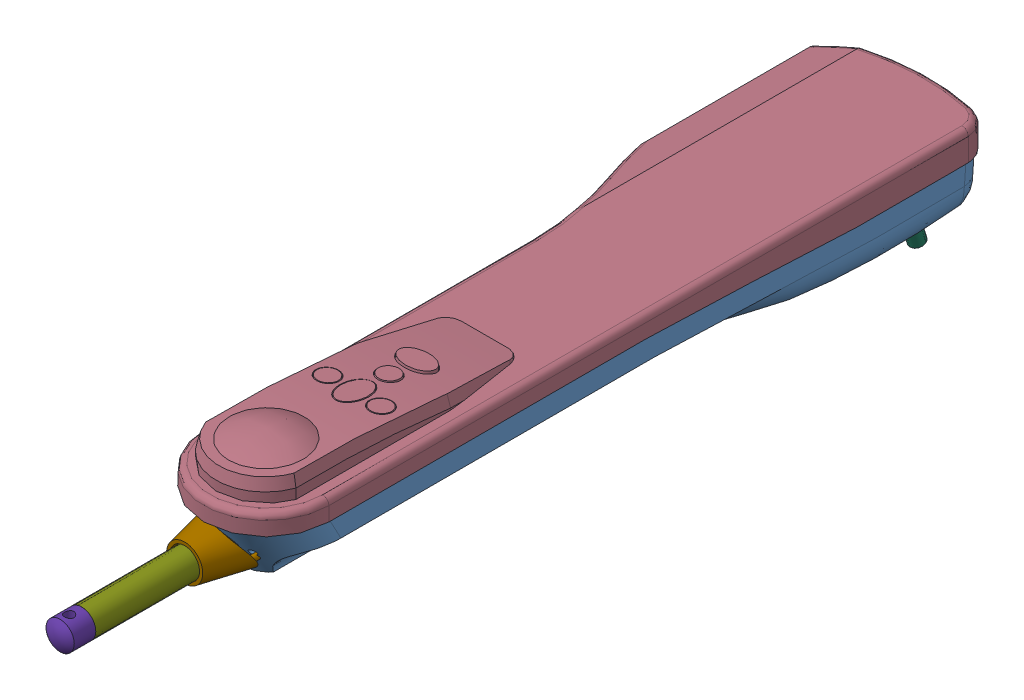
SolidWorks assembly Pilote TP32, configuration Défaut. Lengths in mm.
Overall size (325.02 222.78 564.18).
45 component instances, 32 part files, 10 mates.
Components (placement in the parent):
- Ensemble Corps-1: Ensemble Corps [Défaut] at (159.5823 0 0) size (112.28 81.59 477)
  - Corps inferieur-1: Corps inferieur [Défaut] at (-31.3098 25.3823 221.5951) size (108.71 61.09 460.03)
  - Moteur-1: Moteur [Défaut] at (-71.4902 8.9301 -224.9697) x (-0.161718 -0.986837 0) z (-0.986837 0.161718 0) size (45.24 78 42)
    - Stator-1: Stator [Défaut] at origin size (42 76 42)
    - Silent bloc arrière-1: Silent bloc arrière [Défaut] at (-47.5491 74.546 -21.907) x (-1 0 0) z (0 1 0) size (43 24 6)
    - Silent bloc avant-1: Silent bloc avant [Défaut] at (43.3804 8.5648 -29.3082) x (0.986837 0 -0.161718) z (0 -1 0) size (41.91 24 4)
  - Platine support mécanisme-1: Platine support mécanisme [Défaut] at (-69.0243 -0.8321 -116.8686) x (0 1 0) z (0 0 -1) size (40 82.94 3)
  - Boitier de roulement-1: Boitier de roulement [Défaut] at (-48.4968 0.708 -119.8686) x (0 1 0) z (0 0 -1) size (26 49 9.8)
  - Silent bloc platine-1: Silent bloc platine [Défaut] at (-120.015 23.0186 -118.9936) x (0.999967 -0.008169 0) z (0 0 1) size (86.92 44.57 7)
  - Vis2-6: Vis2 [ISO 7045 - M4 x 8 - Z --- 8C] at (-69.2262 22.7459 -145.3237) x (0 0 -1) z (0.758559 0.651604 0) size (11.02 8 8)
  - Vis2-7: Vis2 [ISO 7045 - M4 x 8 - Z --- 8C] at (-73.7543 -4.8856 -145.3237) x (0 0 -1) z (0.129123 -0.991629 0) size (11.02 8 8)
  - Nez corps-1: Nez corps [Défaut] at (-27.6719 24.9762 236.5951) x (0.975392 -0.220479 0) z (0 0 1) size (39.06 29.71 34.21)
  - Joint torique 1-1: Joint torique 1 [Défaut] at (-31.3098 8.8823 204.9943) x (0.999468 -0.032609 0) z (-0.032609 -0.999468 0) size (22 2 22)
  - Bague joint-1: Bague joint [Défaut] at (-31.3098 8.8823 202.375) x (0.266202 -0.963917 0) z (-0.963917 -0.266202 0) size (22 2 22)
  - Courroie crantée-2: Courroie crantée [Défaut] at (-31.4968 8.208 -142.0151) x (-0.445662 -0.895201 0) z (0 0 1) size (48.01 66.96 6)
  - Vis2-1: Vis2 [ISO 7045 - M4 x 8 - Z --- 8C] at (-50.9968 16.708 -126.9686) x (0 0 1) z (-0.950299 0.31134 0) size (11.02 8 8)
  - Vis2-2: Vis2 [ISO 7045 - M4 x 8 - Z --- 8C] at (-48.4968 0.708 -126.9686) x (0 0 1) z (-1 0 0) size (11.02 8 8)
  - Vis2-3: Vis2 [ISO 7045 - M4 x 8 - Z --- 8C] at (-14.4968 0.708 -126.9686) x (0 0 1) z (-1 0 0) size (11.02 8 8)
  - Vis2-4: Vis2 [ISO 7045 - M4 x 8 - Z --- 8C] at (-11.9968 16.708 -126.9686) x (0 0 1) z (-1 0 0) size (11.02 8 8)
  - Capot-2: Capot [Défaut] at (0 25.3823 0) x (-1 0 0) z (0 1 0) size (112.28 464.89 51.62)
- Ensemble Axe de Fixation-3: Ensemble Axe de Fixation [Défaut] at (134.8975 -6.3473 -217.0327) x (1 0 0) z (0 -0.301134 0.953582) size (25 68.5 17)
  - Pivot de fixation-1: Pivot de fixation [Défaut] at (5.8751 17.8586 0) size (25 17 17)
  - Axe de fixation-1: Axe de fixation [Défaut] at (-6.6249 -42.1414 0) x (0.468613 0 0.883404) z (0 1 0) size (9.4 9.4 60)
- Ensemble Tige-1: Ensemble Tige [Défaut] at (248.0099 -111.1625 -156.1435) x (0.699722 -0.64916 -0.298295) z (0.446906 0.071979 0.891681) size (133.59 147.97 333.57)
  - Tige de vérin-1: Tige de vérin [Défaut] at (-298.0614 -132.433 363.5002) x (-0.701442 -0.555361 -0.446713) z (0.298295 0.340479 -0.891681) size (18 18 305)
  - Nez vérin-1: Nez vérin [Défaut] at (-333.085 -172.4094 468.1946) x (-0.298295 -0.340479 0.891681) z (0.699722 0.557372 0.446906) size (29 18 18)
  - Guide ecrou-1: Guide ecrou [Défaut] at (-205.0112 -15.4431 71.9036) x (0.701442 0.555361 0.446713) z (-0.298295 -0.340479 0.891681) size (21.55 21.55 6.3)
  - Ecrou à billes-1: Ecrou à billes [Défaut] at (-203.5858 -4.3549 55.9233) x (0.298295 0.340479 -0.891681) z (0.701442 0.555361 0.446713) size (44.4 22 22)
  - Butée arrière-1: Butée arrière [Défaut] at (-195.5928 -15.4737 57.1955) x (0.298295 0.340479 -0.891681) z (0.884079 0.25356 0.392571) size (15 21.5 21.5)
  - Joint torique 2-1: Joint torique 2 [Défaut] at (-201.644 -22.3806 75.284) x (0.298295 0.340479 -0.891681) z (0.874683 0.276411 0.398154) size (2 18.2 18.2)
  - anneau elastique-1: anneau elastique [B27.8M - 3DM1-14] at (-200.1907 -20.7219 70.9398) x (0.952962 -0.053689 0.298295) z (-0.298295 -0.340479 0.891681) size (16.83 18.54 1.3)
- Ensemble Vis d'entrainement-1: Ensemble Vis d'entrainement [Défaut] at (128.0856 8.208 -145.9049) x (-0.940711 -0.339209 0) z (0 0 1) size (59.55 59.55 359)
  - Vis d'entrainement-1: Vis d'entrainement [Défaut] at origin size (9.84 9.99 359)
  - Poulie réceptrice Z=71-1: Poulie réceptrice Z=71 [Défaut] at (0 0 13) x (0.412855 0.910797 0) z (0 0 -1) size (44.99 44.99 20)
  - Guide avant de vis-1: Guide avant de vis [Défaut] at (0 0 362.6738) x (0 0 1) z (0 1 0) size (8 15 15)
  - Entretoise-1: Entretoise [Défaut] at (0 0 326.0926) x (0 0 -1) z (0.824754 -0.565492 0) size (10 15 15)
  - Guide arrière de vis-1: Guide arrière de vis [Défaut] at (0 0 323.2936) x (0 0 -1) z (0.982975 -0.183737 0) size (2 15 15)
  - Goupille-1: Goupille [Default] at (0 -7.5 356) x (0 1 0) z (0.979139 0 0.203193) size (15 2 2)
  - Goupille-2: Goupille [Default] at (0 -5.5 2) x (0 1 0) z (0.353829 0 -0.93531) size (15 2 2)
  - Roulement a billes 6BC02-1: Roulement a billes 6BC02 [Défaut] at (0 0 20) x (0 0 1) z (-1 0 0) size (6.01 19 19)
- Ensemble Axe Moteur-1: Ensemble Axe Moteur [Défaut] at (61.9086 37.0085 -159.5872) x (0 0 1) z (-0.731354 -0.681998 0) size (90 38 38)
  - Rotor-1: Rotor [Défaut] at origin size (90 38 38)
  - Poulie motrice-1: Poulie motrice [Défaut] at (48.8884 -27.0093 0) size (11 14 14)
    - Poulie motrice Z=20-1: Poulie motrice Z=20 [Défaut] at origin size (11 12.54 12.54)
    - Flasque poulie-1: Flasque poulie [Défaut] at (-16.112 -39.2783 0) size (1.5 14 14)
Mates (geometry in assembly coordinates):
- Coaxial6: concentric anti-aligned: cylinder of Ensemble Corps-1/Moteur-1/Stator-1 through (88.0921 8.9301 -143.0345) axis (0 0 1) radius 1.25; cylinder of Ensemble Axe Moteur-1/Rotor-1 through (88.0921 8.9301 -266.7385) axis (0 0 -1) radius 2.5
- Distance2: distance = 2 mm anti-aligned: plane of Ensemble Corps-1/Moteur-1/Stator-1 through (89.0624 14.8512 -146.4237) normal (0 0 1); plane of Ensemble Axe Moteur-1/Poulie motrice-1/Poulie motrice Z=20-1 through (86.3871 10.7585 -144.4237) normal (0 0 -1)
- Coïncidente6: coincident aligned: line of Ensemble Corps-1 through (159.5823 0 0) axis (0 0 1)
- Coïncidente7: coincident aligned: line of Ensemble Corps-1 through (-1000 159.5823 0) axis (0 0 1)
- Coaxial7: concentric anti-aligned: cylinder of Ensemble Corps-1/Platine support mécanisme-1 through (128.0856 8.208 -116.8686) axis (0 0 -1) radius 5.5; cylinder of Ensemble Vis d'entrainement-1/Roulement a billes 6BC02-1 through (128.0856 8.208 -122.9049) axis (0 0 1) radius 9.5
- Coaxial8: concentric aligned: cylinder of Ensemble Tige-1/Tige de vérin-1 through (128.0856 8.208 -3.0165) axis (0 0 1) radius 9; cylinder of Ensemble Vis d'entrainement-1/Entretoise-1 through (128.0856 8.208 227.7145) axis (0 0 1) radius 7.5
- Coïncidente9: coincident aligned: plane of Ensemble Corps-1/Corps inferieur-1 through (115.7725 18.6823 -202.9049) normal (-1 0 0); plane of Ensemble Axe de Fixation-3/Pivot de fixation-1 through (115.7725 4.484 -213.6123) normal (-1 0 0)
- Parallèle2: parallel aligned: plane of Ensemble Corps-1/Corps inferieur-1 through (139.0225 11.6823 -97.9049) normal (1 0 0); plane of Ensemble Tige-1/Guide ecrou-1 through (138.8356 12.458 -25.6165) normal (1 0 0)
- Coïncidente11: coincident aligned: plane of Ensemble Corps-1/Corps inferieur-1 through (63.2725 18.6823 -145.9049) normal (0 0 -1); plane of Ensemble Vis d'entrainement-1/Poulie réceptrice Z=71-1 through (158.6834 8.8654 -145.9049) normal (0 0 -1)
- Angle1: planar angle = 2.391101 rad aligned: line of Ensemble Axe Moteur-1/Poulie motrice-1/Poulie motrice Z=20-1 through (80.329 17.2551 -110.6988) axis (-0.731354 -0.681998 0)
